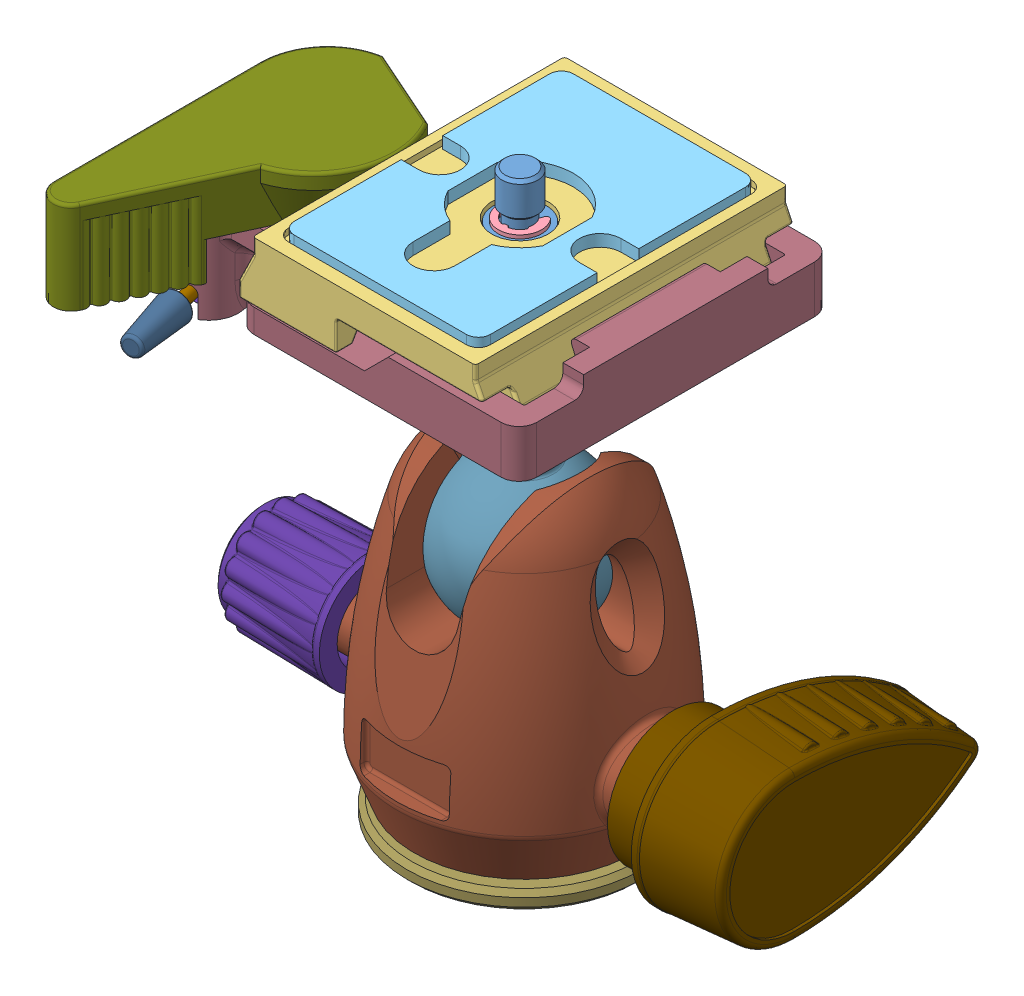
SolidWorks assembly Manfrotto - 494RC2 Head Assy, configuration Predeterminado. Lengths in mm.
Overall size (91.96 94.5 69.28).
23 component instances, 18 part files, 0 mates.
Components (placement in the parent):
- Manfrotto - 494RC2 Head Assy.stp-1: Manfrotto - 494RC2 Head Assy.stp [Predeterminado] at origin size (91.96 94.5 69.28)
  - Quick Release Assy.stp-1: Quick Release Assy.stp [Predeterminado] at (-0.7213 41 0) x (-1 0 0) z (0 0 -1) size (42.4 16.85 52.52)
    - Thumb Screw Assy.stp-1: Thumb Screw Assy.stp [Predeterminado] at (0 -1.5 0) x (0 0 -1) z (-1 0 0) size (29.5 16 20.75)
      - Thumb Screw.stp-1: Thumb Screw.stp [Predeterminado] at origin size (15.01 16 15)
      - Thumb Screw Handle.stp-1: Thumb Screw Handle.stp [Predeterminado] at (0 1 0) size (29.5 2.5 14.5)
    - Quick Release Mounting.stp-1: Quick Release Mounting.stp [Predeterminado] at origin size (42.4 10.35 52.52)
    - IS 3075-3 3.2.stp-1: IS 3075-3 3.2.stp [Predeterminado] at (0 3.5 -1.9764) x (1 0 0) z (0 1 0) size (7.3 6.15 0.6)
    - Quick Release Rubber Pad.stp-1: Quick Release Rubber Pad.stp [Predeterminado] at (0 5 0) x (-1 0 0) z (0 0 -1) size (33 2 47)
  - Manfrotto Logo 01.stp-1: Manfrotto Logo 01.stp [Predeterminado] at (0 -22 -19) x (-1 0 0) z (0 -1 0) size (8.5 1.8 8.5)
    - Manfrotto Logo 01 - 1.stp-1: Manfrotto Logo 01 - 1.stp [Predeterminado] at origin size (8.5 0.3 8.5)
    - Manfrotto Logo 01 - 2.stp-1: Manfrotto Logo 01 - 2.stp [Predeterminado] at (0 1.05 0) x (0 0 1) z (-1 0 0) size (8.5 1.5 8.5)
  - Locking Pin Assy.stp-1: Locking Pin Assy.stp [Predeterminado] at (-40.5 28.5 12.6) x (0.97437 0 -0.224951) z (0.224951 0 0.97437) size (7 17 21)
    - Locking Pin.stp-1: Locking Pin.stp [Predeterminado] at origin size (7 17 7)
    - Locking Pin Lever.stp-1: Locking Pin Lever.stp [Predeterminado] at (0 -5.5 6) x (1 0 0) z (0 1 0) size (2 17 2)
    - Locking Pin Lever Rubber.stp-1: Locking Pin Lever Rubber.stp [Predeterminado] at (0 -5.5 12.5) size (4.96 4.96 10)
  - Base Casting.stp-1: Base Casting.stp [Predeterminado] at origin size (64 51.03 43.02)
  - Base Plate.stp-1: Base Plate.stp [Predeterminado] at (0 -40.5 0) size (39.5 19 39.5)
  - Mount Casting.stp-1: Mount Casting.stp [Predeterminado] at (0 36 0) size (71.96 24.08 53.67)
  - Ball Joint.stp-1: Ball Joint.stp [Predeterminado] at (0 -1 0) size (25 40.5 25)
  - ISO 10642 M5 x  16.stp-1: ISO 10642 M5 x  16.stp [Predeterminado] at (0 34.6 0) x (0 -1 0) z (0 0 1) size (16 9.43 9.43)
  - Quick Release Catch.stp-1: Quick Release Catch.stp [Predeterminado] at (-34 40.5 -0.9) size (25 15.5 49)
  - Friction Knob.stp-1: Friction Knob.stp [Predeterminado] at (-25 -26 0) x (0 1 0) z (0 0 1) size (19.07 19 19.04)
  - Locking Knob.stp-1: Locking Knob.stp [Predeterminado] at (31.5 -25 0) x (0 1 0) z (0 0 -1) size (27.31 20.5 46)
